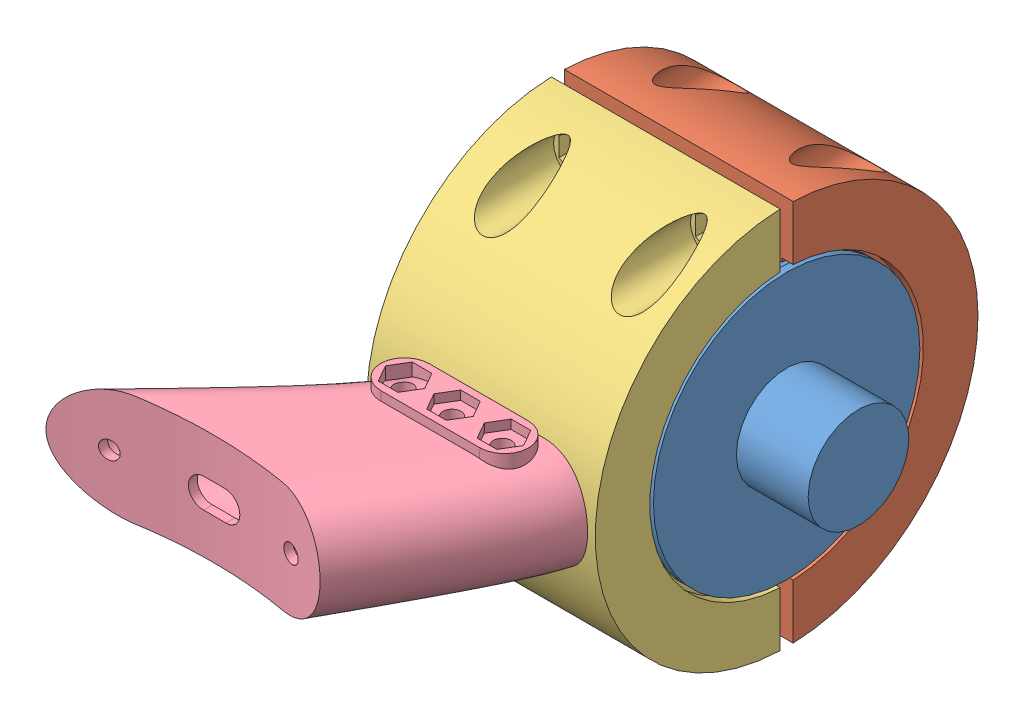
SolidWorks assembly edf, configuration Default. Lengths in mm.
Overall size (128.85 108.65 164.32).
4 component instances, 4 part files, 7 mates.
Components (placement in the parent):
- edf-1: edf [Default] at (17.7715 0 -26.4391) size (85.4 90.8 94.1)
- Part2^edf-1: Part2^edf [Default] at origin size (65 108.65 52.51) (virtual)
- Copy of Part2^edf-2: Copy of Part2^edf [Default] at (-3.166 0 -52.8782) x (1 0 0) z (0 0 -1) size (65 108.65 65.01) (virtual)
- Part3^edf-1: Part3^edf [Default] at (19.6134 0 24.3609) size (107.45 39.55 60.19) (virtual)
Mates (geometry in assembly coordinates):
- Coincident1: coincident aligned: plane of edf-1 through (17.7715 0 -26.4391) normal (0 1 0)
- Coincident2: coincident aligned: plane of edf-1 through (17.7715 0 -26.4391) normal (0 1 0); plane of Part2^edf-1 through (0 0 0) normal (0 1 0)
- Concentric1: concentric aligned: cylinder of edf-1 through (82.7715 0 -26.4391) axis (-1 0 0) radius 36.83; cylinder of Copy of Part2^edf-2 through (17.7715 0 -26.4391) axis (-1 0 0) radius 37.846
- Coincident3: coincident aligned: plane of Part2^edf-1 through (79.6055 26.4391 -26.4391) normal (1 0 0); plane of Copy of Part2^edf-2 through (79.6055 26.4391 -26.4391) normal (1 0 0)
- Parallel1: parallel anti-aligned: plane of Part2^edf-1 through (17.7715 0 -28.2871) normal (0 0 1); plane of Copy of Part2^edf-2 through (14.6055 0 -24.5911) normal (0 0 -1)
- Coincident4: coincident anti-aligned: plane of Copy of Part2^edf-2 through (-3.166 0 -52.8782) normal (0 -1 0); plane of Part3^edf-1 through (19.6134 0 24.3609) normal (0 1 0)
- Concentric2: concentric aligned: cylinder of Copy of Part2^edf-2 through (17.7715 0 -26.4391) axis (-1 0 0) radius 54.356; cylinder of Part3^edf-1 through (81.7709 0 -26.4391) axis (-1 0 0) radius 54.356
